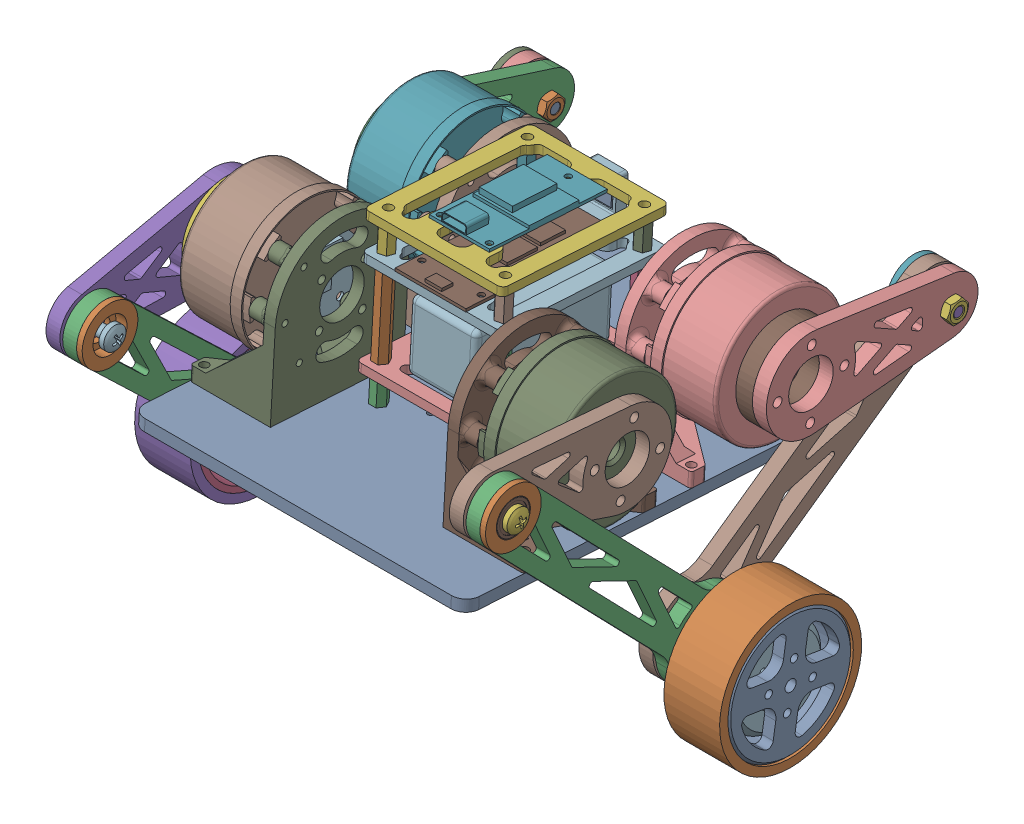
SolidWorks assembly FOC_URDF, configuration Default. Lengths in mm.
Overall size (212 139 186.61).
11 component instances, 6 part files, 22 mates.
Components (placement in the parent):
- leg1-1: leg1 [默认] at (-12.3008 -167.6966 112.8834) x (1 0 0) z (0 0.026645 0.999645) size (19.27 34.06 75.35)
- leg2-1: leg2 [默认] at (-12.3008 -164.3239 113.811) x (1 0 0) z (0 0.068499 0.997651) size (22 94.89 103.36)
- leg3-1: leg3 [默认] at (-12.3008 -164.3067 114.2243) x (1 0 0) z (0 0.059106 0.998252) size (19.27 93.02 104.99)
- leg4-1: leg4 [默认] at (-12.3008 -167.9765 115.6851) x (1 0 0) z (0 0.106765 0.994284) size (11 35.93 75)
- mainframe-1: mainframe [默认] at (-12.3008 -166.6787 113.9419) x (1 0 0) z (0 0.059002 0.998258) size (133 67 150)
- tire-1: tire [默认] at (-12.8008 -164.2881 116.8236) size (24 51 51)
- leg1-2: leg1 [默认] at (-12.3008 -173.4682 126.081) x (-1 0 0) z (0 -0.358813 -0.933409) size (19.27 34.06 75.35)
- leg2-2: leg2 [默认] at (-12.3008 -152.4459 113.5935) x (-1 0 0) z (0 -0.07297 -0.997334) size (22 94.89 103.36)
- leg3-2: leg3 [默认] at (-12.3008 -152.5234 112.8503) x (-1 0 0) z (0 -0.089911 -0.99595) size (19.27 93.02 104.99)
- leg4-2: leg4 [默认] at (-12.3008 -173.2591 105.5328) x (-1 0 0) z (0 0.176077 -0.984376) size (11 35.93 75)
- tire-2: tire [默认] at (-11.8008 -240.1506 118.7668) x (-1 0 0) z (0 0 1) size (24 51 51)
Mates (geometry in assembly coordinates):
- Coincident1: coincident anti-aligned: plane of leg1-1 through (-78.8008 -134.508 81.9881) normal (1 0 0); plane of mainframe-1 through (-78.8008 -134.508 81.9881) normal (-1 0 0)
- Concentric1: concentric anti-aligned: cylinder of leg1-1 through (-83.8008 -134.508 81.9881) axis (1 0 0) radius 8; cylinder of mainframe-1 through (-59.8008 -134.508 81.9881) axis (-1 0 0) radius 3.3
- Concentric2: concentric anti-aligned: cylinder of leg1-1 through (-90.385 -143.8782 32.874) axis (1 0 0) radius 2; cylinder of leg2-1 through (-92.0008 -143.8782 32.874) axis (-1 0 0) radius 2
- Coincident2: coincident anti-aligned: plane of leg1-1 through (-85.8008 -143.8782 32.874) normal (-1 0 0); plane of leg2-1 through (-85.8008 -208.235 115.839) normal (1 0 0)
- Coincident3: coincident anti-aligned: plane of leg4-1 through (-78.8008 -130.9679 141.8836) normal (1 0 0); plane of mainframe-1 through (-78.8008 -130.9679 141.8836) normal (-1 0 0)
- Concentric3: concentric aligned: cylinder of leg4-1 through (-84.8008 -130.9679 141.8836) axis (-1 0 0) radius 8; cylinder of mainframe-1 through (-59.8008 -130.9679 141.8836) axis (-1 0 0) radius 3.3
- Concentric4: concentric aligned: cylinder of leg3-1 through (-78.2166 -135.606 191.668) axis (-1 0 0) radius 2; cylinder of leg4-1 through (-86.8008 -135.606 191.668) axis (-1 0 0) radius 2.1
- Coincident4: coincident anti-aligned: plane of leg3-1 through (-86.8008 -135.606 191.668) normal (-1 0 0); plane of leg4-1 through (-86.8008 -130.9679 141.8836) normal (1 0 0)
- Concentric5: concentric anti-aligned: cylinder of leg2-1 through (-84.8008 -208.235 115.839) axis (-1 0 0) radius 15; cylinder of leg3-1 through (-83.8008 -208.235 115.839) axis (1 0 0) radius 15
- Concentric6: concentric aligned: cylinder of leg2-1 through (-84.8008 -208.235 115.839) axis (-1 0 0) radius 15; cylinder of tire-1 through (-98.3008 -208.235 115.839) axis (-1 0 0) radius 2
- Coincident5: coincident anti-aligned: plane of leg2-1 through (-94.3008 -208.235 115.839) normal (-1 0 0); plane of tire-1 through (-94.3008 -208.235 115.839) normal (1 0 0)
- Coincident6: coincident anti-aligned: plane of mainframe-1 through (54.1992 -134.508 81.9881) normal (1 0 0); plane of leg4-2 through (54.1992 -134.508 81.9881) normal (-1 0 0)
- Concentric7: concentric aligned: cylinder of mainframe-1 through (35.1992 -134.508 81.9881) axis (1 0 0) radius 3.3; cylinder of leg4-2 through (60.1992 -134.508 81.9881) axis (1 0 0) radius 8
- Coincident7: coincident anti-aligned: plane of mainframe-1 through (54.1992 -130.9679 141.8836) normal (1 0 0); plane of leg1-2 through (54.1992 -130.9679 141.8836) normal (-1 0 0)
- Concentric8: concentric anti-aligned: cylinder of mainframe-1 through (35.1992 -130.9679 141.8836) axis (1 0 0) radius 3.3; cylinder of leg1-2 through (59.1992 -130.9679 141.8836) axis (-1 0 0) radius 8
- Concentric9: concentric anti-aligned: cylinder of leg1-2 through (65.7834 -120.7834 190.8354) axis (-1 0 0) radius 2; cylinder of leg2-2 through (67.3992 -120.7834 190.8354) axis (1 0 0) radius 2
- Coincident8: coincident anti-aligned: plane of leg1-2 through (61.1992 -120.7834 190.8354) normal (1 0 0); plane of leg2-2 through (61.1992 -196.2038 117.7822) normal (-1 0 0)
- Coincident9: coincident anti-aligned: plane of leg3-2 through (62.1992 -135.6512 32.0012) normal (1 0 0); plane of leg4-2 through (62.1992 -134.508 81.9881) normal (-1 0 0)
- Concentric10: concentric aligned: cylinder of leg3-2 through (53.615 -135.6512 32.0012) axis (1 0 0) radius 2; cylinder of leg4-2 through (62.1992 -135.6512 32.0012) axis (1 0 0) radius 2.1
- Concentric11: concentric anti-aligned: cylinder of leg2-2 through (64.5992 -196.2038 117.7822) axis (1 0 0) radius 2; cylinder of leg3-2 through (57.6992 -196.2038 117.7822) axis (-1 0 0) radius 2.1
- Coincident10: coincident anti-aligned: plane of leg2-2 through (69.6992 -196.2038 117.7822) normal (1 0 0); plane of tire-2 through (69.6992 -196.2038 117.7822) normal (-1 0 0)
- Concentric12: concentric aligned: cylinder of leg2-2 through (60.1992 -196.2038 117.7822) axis (1 0 0) radius 15; cylinder of tire-2 through (73.6992 -196.2038 117.7822) axis (1 0 0) radius 25.5
